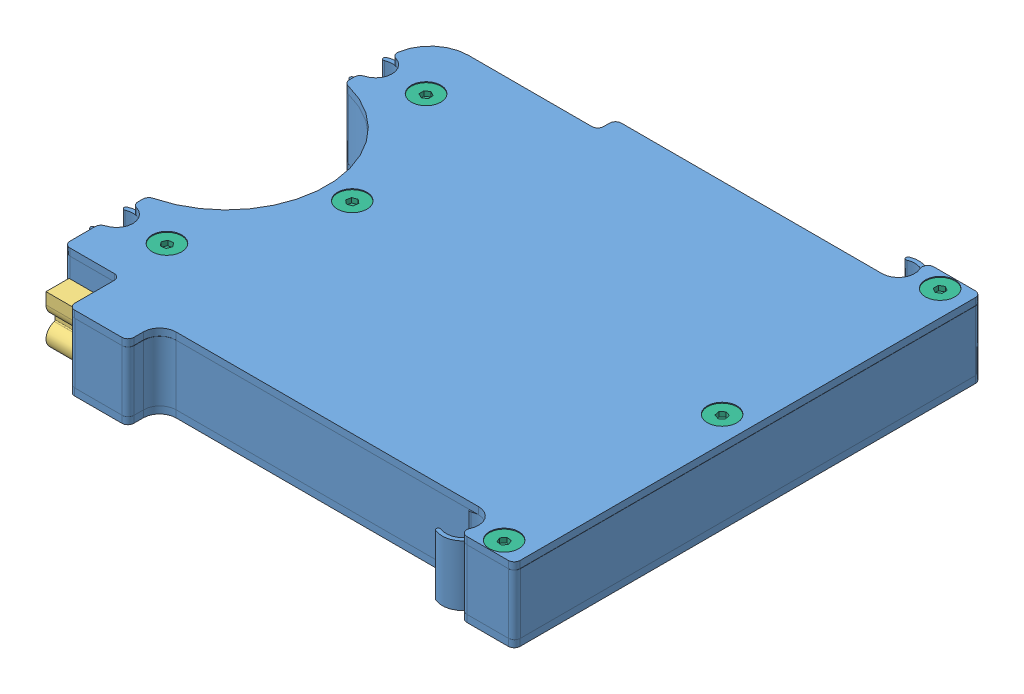
SolidWorks assembly battery, configuration Default. Lengths in mm.
Overall size (86.44 12.6 80.66).
27 component instances, 6 part files, 78 mates.
Components (placement in the parent):
- battery-layer-1: battery-layer [Bottom] at origin size (84.85 1.2 79)
- battery-cell-1: battery-cell [Default] at (-16.8 0.6 18.43) size (55 5 30)
- battery-cell-2: battery-cell [Default] at (-16.8 5.6 18.43) size (55 5 30)
- battery-cell-3: battery-cell [Default] at (-16.8 0.6 -18.43) size (55 5 30)
- battery-cell-4: battery-cell [Default] at (-16.8 5.6 -18.43) size (55 5 30)
- xt30-female-1: xt30-female [Default] at (-60.552 5.675 35.4) x (0 -1 0) z (0 0 -1) size (10.15 12.4 5.2)
- insert-m2.5-10mm-1: insert-m2.5-10mm [Default] at (-64.8875 5.8 21.92) x (-0.837169 0 -0.546944) z (-0.546944 0 0.837169) size (3.6 10 3.58)
- insert-m2.5-10mm-2: insert-m2.5-10mm [Default] at (-64.8875 5.8 -21.92) x (0.796688 0 -0.60439) z (-0.60439 0 -0.796688) size (3.6 10 3.58)
- insert-m2.5-10mm-3: insert-m2.5-10mm [Default] at (7.1125 5.8 -36.88) x (0.567774 0 -0.823184) z (0.823184 0 0.567774) size (3.6 10 3.58)
- insert-m2.5-10mm-4: insert-m2.5-10mm [Default] at (7.1125 5.8 36.88) x (0.900947 0 -0.43393) z (0.43393 0 0.900947) size (3.6 10 3.58)
- insert-m2.5-10mm-7: insert-m2.5-10mm [Default] at (7.1125 5.8 0) x (0.979648 0 -0.200723) z (0.200723 0 0.979648) size (3.6 10 3.58)
- battery-layer-3: battery-layer [Top] at (0 11.4 0) size (84.85 1.2 79)
- balance-plug-1: balance-plug [Default] at (-54.5375 8.1 -14.03) x (-1 0 0) z (0 -1 0) size (16 17.1 5.7)
- insert-m2.5-10mm-8: insert-m2.5-10mm [Default] at (-55.4595 5.8 0) x (0.476124 0 -0.879378) z (0.879378 0 0.476124) size (3.6 10 3.58)
- battery-layer-4: battery-layer [Core] at (0.0375 1.2 0) size (86.44 10.2 80.66)
- countersunk-screw-m2.5-6mm-1: countersunk-screw-m2.5-6mm [Default] at (7.075 11.85 -36.88) x (0 -1 0) z (0 0 1) size (6 5 5)
- countersunk-screw-m2.5-6mm-2: countersunk-screw-m2.5-6mm [Default] at (7.075 11.85 0) x (0 -1 0) z (0.188455 0 0.982082) size (6 5 5)
- countersunk-screw-m2.5-6mm-4: countersunk-screw-m2.5-6mm [Default] at (7.075 11.85 36.88) x (0 -1 0) z (0.395734 0 0.918365) size (6 5 5)
- countersunk-screw-m2.5-6mm-6: countersunk-screw-m2.5-6mm [Default] at (-64.925 11.85 21.92) x (0 -1 0) z (0.6 0 0.8) size (6 5 5)
- countersunk-screw-m2.5-6mm-8: countersunk-screw-m2.5-6mm [Default] at (-55.497 11.85 0) x (0 -1 0) z (0.773678 0 0.63358) size (6 5 5)
- countersunk-screw-m2.5-6mm-10: countersunk-screw-m2.5-6mm [Default] at (-64.925 11.85 -21.92) x (0 -1 0) z (0.896211 0 0.443629) size (6 5 5)
- countersunk-screw-m2.5-6mm-12: countersunk-screw-m2.5-6mm [Default] at (7.075 -0.45 -36.88) x (0 1 0) z (1 0 0) size (6 5 5)
- countersunk-screw-m2.5-6mm-14: countersunk-screw-m2.5-6mm [Default] at (7.075 -0.45 0) x (0 1 0) z (1 0 0) size (6 5 5)
- countersunk-screw-m2.5-6mm-16: countersunk-screw-m2.5-6mm [Default] at (7.075 -0.45 36.88) x (0 1 0) z (1 0 0) size (6 5 5)
- countersunk-screw-m2.5-6mm-18: countersunk-screw-m2.5-6mm [Default] at (-64.925 -0.45 -21.92) x (0 1 0) z (0.837169 0 0.546944) size (6 5 5)
- countersunk-screw-m2.5-6mm-20: countersunk-screw-m2.5-6mm [Default] at (-55.497 -0.45 0) x (0 1 0) z (1 0 0) size (6 5 5)
- countersunk-screw-m2.5-6mm-22: countersunk-screw-m2.5-6mm [Default] at (-64.925 -0.45 21.92) x (0 1 0) z (1 0 0) size (6 5 5)
Mates (geometry in assembly coordinates):
- Coincident1: coincident: plane of battery-layer-1 through (0 0.6 0) normal (0 1 0); plane of battery-cell-1 through (-16.8 0.6 18.43) normal (0 -1 0)
- Coincident2: coincident: plane of battery-cell-1 through (-16.8 5.6 18.43) normal (0 1 0); plane of battery-cell-2 through (-16.8 5.6 18.43) normal (0 -1 0)
- Coincident3: coincident: plane of battery-cell-1 through (-44.3 5.6 33.43) normal (0 0 1); plane of battery-cell-2 through (-44.3 10.6 33.43) normal (0 0 1)
- Coincident4: coincident: plane of battery-cell-1 through (10.7 5.6 3.43) normal (1 0 0); plane of battery-cell-2 through (10.7 10.6 3.43) normal (1 0 0)
- Coincident5: coincident: plane of battery-cell-3 through (-16.8 5.6 -18.43) normal (0 1 0); plane of battery-cell-4 through (-16.8 5.6 -18.43) normal (0 -1 0)
- Coincident7: coincident: plane of battery-cell-3 through (10.7 5.6 -33.43) normal (1 0 0); plane of battery-cell-4 through (10.7 10.6 -33.43) normal (1 0 0)
- Coincident8: coincident: plane of battery-layer-1 through (0 0.6 0) normal (0 1 0); plane of battery-cell-3 through (-16.8 0.6 -18.43) normal (0 -1 0)
- Parallel1: parallel: plane of battery-cell-1 through (10.7 5.6 3.43) normal (1 0 0); plane of assembly through (0 0 0) normal (1 0 0)
- Coincident14: coincident: plane of battery-cell-1 through (10.7 5.6 3.43) normal (1 0 0); plane of battery-cell-3 through (10.7 5.6 -33.43) normal (1 0 0)
- Coincident19: coincident: plane of battery-layer-1 through (-63.952 0.6 0) normal (-1 0 0); plane of xt30-female-1 through (-63.952 5.675 35.4) normal (-1 0 0)
- InPlace1: in place: plane of battery-layer-1 through (0 1 0) normal (0 1 0); plane of ? through (0 1 0) normal (0 1 0); moOrthogonalPlaneRef_w of battery-layer-1 through (0 1 0) normal (0 1 0); plane of ? through (0 1 0) normal (0 0 -1); plane of battery-layer-1 through (0 1 0) normal (0 1 0); plane of ? through (0 1 0) normal (1 0 0); plane of battery-layer-1 through (0 0.5 0) normal (0 1 0); unknown of ?
- Coincident20: coincident: plane of battery-layer-1; plane of ?
- Coincident21: coincident: moOrthogonalPlaneRef_w of battery-layer-1 through (0 0.5 0) normal (0 0 -1); plane of ? through (0 0.5 0) normal (0 0 -1)
- Coincident22: coincident: moOrthogonalPlaneRef_w of battery-layer-1 through (0 0.5 0) normal (-1 0 0); plane of ? through (0 0.5 0) normal (1 0 0)
- Concentric1: concentric: cylinder of ? through (-64.925 10.65 21.92) axis (0 -1 0) radius 1.9; cylinder of insert-m2.5-10mm-1 through (-64.925 9.64 21.92) axis (0 -1 0) radius 1.25
- Coincident25: coincident: plane of ? through (0 10.65 0) normal (0 1 0); plane of insert-m2.5-10mm-2 through (-64.925 10.65 -21.92) normal (0 1 0)
- Concentric2: concentric: cylinder of ? through (-64.925 10.65 -21.92) axis (0 -1 0) radius 1.9; cylinder of insert-m2.5-10mm-2 through (-64.925 9.64 -21.92) axis (0 -1 0) radius 1.25
- Coincident26: coincident: plane of ? through (0 10.65 0) normal (0 1 0); plane of insert-m2.5-10mm-3
- Concentric3: concentric: cylinder of ? through (7.075 10.65 -36.88) axis (0 -1 0) radius 1.9; cylinder of insert-m2.5-10mm-3 through (7.075 9.64 -36.88) axis (0 -1 0) radius 1.25
- Coincident27: coincident: plane of ? through (0 10.65 0) normal (0 1 0); plane of insert-m2.5-10mm-4
- Concentric4: concentric: cylinder of ? through (7.075 10.65 36.88) axis (0 -1 0) radius 1.9; cylinder of insert-m2.5-10mm-4 through (7.075 9.64 36.88) axis (0 -1 0) radius 1.25
- Coincident29: coincident: plane of ? through (0 10.65 0) normal (0 1 0); plane of insert-m2.5-10mm-7
- Concentric6: concentric: cylinder of ? through (7.075 10.65 0) axis (0 -1 0) radius 1.9; cylinder of insert-m2.5-10mm-7 through (7.075 9.64 0) axis (0 -1 0) radius 1.25
- Coincident31: coincident: plane of battery-layer-1 through (0 0.6 0) normal (0 1 0); plane of xt30-female-1 through (-69.952 0.6 35.4) normal (0 -1 0)
- Distance4: distance = 1.5 mm: plane of xt30-female-1 through (-69.952 5.675 38) normal (0 0 1); plane of battery-layer-1 through (0 0.6 39.5) normal (0 0 1)
- Coincident33: coincident: plane of battery-cell-3 through (-44.3 5.6 -3.43) normal (0 0 1); plane of battery-cell-4 through (-44.3 10.6 -3.43) normal (0 0 1)
- Coincident37: coincident: plane of battery-cell-1 through (-44.3 5.5 2.6) normal (0 0 -1); plane of ? through (0 10.65 2.6) normal (0 0 1)
- Coincident38: coincident: plane of battery-cell-3 through (-44.3 5.5 -2.6) normal (0 0 1); plane of ? through (0 10.65 -2.6) normal (0 0 -1)
- Coincident39: coincident: plane of battery-cell-1 through (10.7 5.5 2.6) normal (1 0 0); plane of ? through (10.7 10.65 0) normal (1 0 0)
- Coincident41: coincident: plane of ? through (0 10.65 0) normal (0 1 0); plane of battery-layer-3 through (0 10.65 0) normal (0 -1 0)
- Concentric7: concentric: circle of battery-layer-1; circle of battery-layer-3
- Concentric8: concentric: circle of battery-layer-1; circle of battery-layer-3
- Coincident44: coincident: cone of battery-layer-3 through (-64.925 11.6 -21.92) axis (0 -1 0); cone of ? through (-64.925 10.6 -21.92) axis (0 -1 0)
- Coincident45: coincident: cone of battery-layer-3 through (7.075 11.6 -36.88) axis (0 -1 0); cone of ? through (7.075 10.6 -36.88) axis (0 -1 0)
- Coincident46: coincident: cone of battery-layer-3 through (7.075 11.6 0) axis (0 -1 0); cone of ? through (7.075 10.6 0) axis (0 -1 0)
- Coincident47: coincident: cone of battery-layer-3 through (7.075 11.6 36.88) axis (0 -1 0); cone of ? through (7.075 10.6 36.88) axis (0 -1 0)
- Coincident48: coincident: cone of battery-layer-3 through (-64.925 11.6 21.92) axis (0 -1 0); cone of ? through (-64.925 10.6 21.92) axis (0 -1 0)
- Coincident49: coincident: cone of battery-layer-1 through (-64.925 -0.4 21.92) axis (0 1 0); cone of ? through (-64.925 0.6 21.92) axis (0 1 0)
- Coincident50: coincident: cone of battery-layer-1 through (-64.925 -0.4 -21.92) axis (0 1 0); cone of ? through (-64.925 0.6 -21.92) axis (0 1 0)
- Coincident51: coincident: cone of battery-layer-1 through (7.075 -0.4 36.88) axis (0 1 0); cone of ? through (7.075 0.6 36.88) axis (0 1 0)
- Coincident52: coincident: cone of battery-layer-1 through (7.075 -0.4 0) axis (0 1 0); cone of ? through (7.075 0.6 0) axis (0 1 0)
- Coincident53: coincident: cone of battery-layer-1 through (7.075 -0.4 -36.88) axis (0 1 0); cone of ? through (7.075 0.6 -36.88) axis (0 1 0)
- Coincident54: coincident: plane of battery-layer-1 through (0 0.6 -31.13) normal (0 0 -1); plane of balance-plug-1 through (-54.5375 8.1 -31.13) normal (0 0 -1)
- Distance6: distance = 0.7 mm: plane of battery-cell-3 through (10.7 5.6 -33.43) normal (1 0 0); plane of battery-layer-1 through (11.4 0.6 0) normal (1 0 0)
- Distance7: distance = 0.7 mm: plane of battery-cell-3 through (-44.3 5.6 -33.43) normal (0 0 -1); plane of battery-layer-1 through (0 0.6 -34.13) normal (0 0 -1)
- Distance8: distance = 0.7 mm: plane of battery-cell-1 through (-44.3 5.6 33.43) normal (0 0 1); plane of battery-layer-1 through (0 0.6 34.13) normal (0 0 1)
- Concentric11: concentric: cylinder of insert-m2.5-10mm-3 through (7.1125 10.8 -36.88) axis (0 -1 0) radius 1.575; cylinder of battery-layer-4 through (7.1125 0.599 -36.88) axis (0 1 0) radius 1.875
- Concentric12: concentric: cylinder of insert-m2.5-10mm-7 through (7.1125 10.8 0) axis (0 -1 0) radius 1.575; cylinder of battery-layer-4 through (7.1125 0.599 0) axis (0 1 0) radius 1.875
- Concentric13: concentric: cylinder of insert-m2.5-10mm-4 through (7.1125 10.8 36.88) axis (0 -1 0) radius 1.575; cylinder of battery-layer-4 through (7.1125 0.599 36.88) axis (0 1 0) radius 1.875
- Concentric14: concentric: cylinder of insert-m2.5-10mm-8 through (-55.4595 10.8 0) axis (0 -1 0) radius 1.575; cylinder of battery-layer-4 through (-55.4595 0.599 0) axis (0 1 0) radius 1.875
- Coincident66: coincident: cone of battery-layer-3 through (-55.497 11.6 0) axis (0 -1 0); cone of ? through (-55.497 10.6 0) axis (0 -1 0)
- Coincident67: coincident: cone of battery-layer-1 through (-55.497 -0.4 0) axis (0 1 0); cone of ? through (-55.497 0.6 0) axis (0 1 0)
- Coincident68: coincident: plane of battery-layer-1 through (0 0.6 0) normal (0 1 0); plane of battery-layer-4 through (0.0375 0.6 0) normal (0 -1 0)
- Concentric15: concentric: cylinder of insert-m2.5-10mm-1 through (-64.8875 0.8 21.92) axis (0 1 0) radius 1.25; cylinder of battery-layer-4 through (-64.8875 0.599 21.92) axis (0 1 0) radius 1.875
- Concentric16: concentric: cylinder of insert-m2.5-10mm-3 through (7.1125 10.8 -36.88) axis (0 -1 0) radius 1.25; cylinder of battery-layer-4 through (7.1125 0.599 -36.88) axis (0 1 0) radius 1.875
- Coincident69: coincident: plane of battery-layer-3 through (0 10.8 0) normal (0 -1 0); plane of battery-layer-4 through (0.0375 10.8 0) normal (0 1 0)
- Coincident72: coincident: plane of balance-plug-1 through (-54.5375 10.8 -14.03) normal (0 1 0); plane of battery-layer-4 through (0.0375 10.8 0) normal (0 1 0)
- Width1: width: plane of battery-layer-4 through (-46.3375 5.2 -13.63) normal (-1 0 0); plane of battery-layer-4 through (-62.7375 5.2 -13.63) normal (1 0 0); plane of balance-plug-1 through (-46.5375 10.1 -31.13) normal (1 0 0); plane of balance-plug-1 through (-62.5375 10.1 -31.13) normal (-1 0 0)
- Concentric17: concentric: cylinder of insert-m2.5-10mm-2 through (-64.8875 0.8 -21.92) axis (0 1 0) radius 1.25; cylinder of battery-layer-4 through (-64.8875 0.599 -21.92) axis (0 1 0) radius 1.875
- Coincident77: coincident: plane of insert-m2.5-10mm-4 through (7.1125 10.8 36.88) normal (0 1 0); plane of battery-layer-4 through (0.0375 10.8 0) normal (0 1 0)
- Coincident78: coincident: plane of insert-m2.5-10mm-7 through (7.1125 10.8 0) normal (0 1 0); plane of battery-layer-4 through (0.0375 10.8 0) normal (0 1 0)
- Coincident79: coincident: plane of insert-m2.5-10mm-3 through (7.1125 10.8 -36.88) normal (0 1 0); plane of battery-layer-4 through (0.0375 10.8 0) normal (0 1 0)
- Coincident80: coincident: plane of insert-m2.5-10mm-2 through (-64.8875 10.8 -21.92) normal (0 1 0); plane of battery-layer-4 through (0.0375 10.8 0) normal (0 1 0)
- Coincident81: coincident: plane of insert-m2.5-10mm-8 through (-55.4595 10.8 0) normal (0 1 0); plane of battery-layer-4 through (0.0375 10.8 0) normal (0 1 0)
- Coincident82: coincident: plane of insert-m2.5-10mm-1 through (-64.8875 10.8 21.92) normal (0 1 0); plane of battery-layer-4 through (0.0375 10.8 0) normal (0 1 0)
- Concentric18: concentric: cylinder of insert-m2.5-10mm-1 through (-64.8875 0.8 21.92) axis (0 1 0) radius 1.25; cylinder of battery-layer-4 through (-64.8875 0.599 21.92) axis (0 1 0) radius 1.875
- Coincident83: coincident: cone of battery-layer-3 through (7.075 11.7 -36.88) axis (0 -1 0); cone of countersunk-screw-m2.5-6mm-1 through (7.075 10.45 -36.88) axis (0 -1 0)
- Coincident84: coincident: cone of battery-layer-3 through (7.075 11.7 0) axis (0 -1 0); cone of countersunk-screw-m2.5-6mm-2 through (7.075 10.45 0) axis (0 -1 0)
- Coincident85: coincident: cone of battery-layer-3 through (7.075 11.7 36.88) axis (0 -1 0); cone of countersunk-screw-m2.5-6mm-4 through (7.075 10.45 36.88) axis (0 -1 0)
- Coincident86: coincident: cone of battery-layer-3 through (-64.925 11.7 21.92) axis (0 -1 0); cone of countersunk-screw-m2.5-6mm-6 through (-64.925 10.45 21.92) axis (0 -1 0)
- Coincident87: coincident: cone of battery-layer-3 through (-55.497 11.7 0) axis (0 -1 0); cone of countersunk-screw-m2.5-6mm-8 through (-55.497 10.45 0) axis (0 -1 0)
- Coincident88: coincident: cone of battery-layer-3 through (-64.925 11.7 -21.92) axis (0 -1 0); cone of countersunk-screw-m2.5-6mm-10 through (-64.925 10.45 -21.92) axis (0 -1 0)
- Coincident89: coincident: cone of battery-layer-1 through (7.075 -0.3 -36.88) axis (0 1 0); cone of countersunk-screw-m2.5-6mm-12 through (7.075 0.95 -36.88) axis (0 1 0)
- Coincident90: coincident: cone of battery-layer-1 through (7.075 -0.3 0) axis (0 1 0); cone of countersunk-screw-m2.5-6mm-14 through (7.075 0.95 0) axis (0 1 0)
- Coincident91: coincident: cone of battery-layer-1 through (7.075 -0.3 36.88) axis (0 1 0); cone of countersunk-screw-m2.5-6mm-16 through (7.075 0.95 36.88) axis (0 1 0)
- Coincident92: coincident: cone of battery-layer-1 through (-64.925 -0.3 -21.92) axis (0 1 0); cone of countersunk-screw-m2.5-6mm-18 through (-64.925 0.95 -21.92) axis (0 1 0)
- Coincident93: coincident: cone of battery-layer-1 through (-55.497 -0.3 0) axis (0 1 0); cone of countersunk-screw-m2.5-6mm-20 through (-55.497 0.95 0) axis (0 1 0)
- Coincident94: coincident: cone of battery-layer-1 through (-64.925 -0.3 21.92) axis (0 1 0); cone of countersunk-screw-m2.5-6mm-22 through (-64.925 0.95 21.92) axis (0 1 0)
